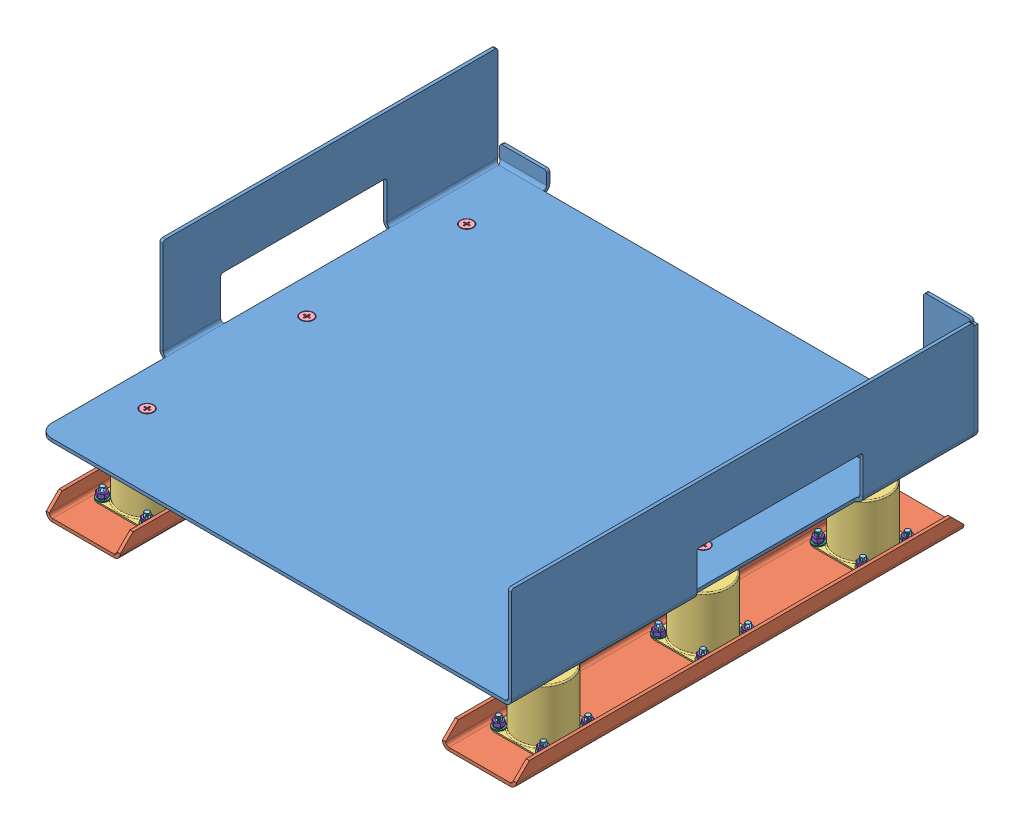
SolidWorks assembly В17.745.058СБ Шасси, configuration По умолчанию. Lengths in mm.
Overall size (375.45 141.9 365.44).
111 component instances, 8 part files, 203 mates.
Components (placement in the parent):
- В17.745.551 Полка-1: В17.745.551 Полка [По умолчанию<Как обработанный>] at (-182.6691 43.1061 558.1681) size (375.45 80.44 365.44)
- В17.745.556 Основание-1: В17.745.556 Основание [По умолчанию] at (-150.1691 -18.3939 375.6681) x (0 0 -1) z (1 0 0) size (350 15 58)
- В17.745.556 Основание-2: В17.745.556 Основание [По умолчанию] at (159.8309 -18.3939 375.6681) x (0 0 1) z (-1 0 0) size (350 15 58)
- В17.745.558 Амортизатор-1: В17.745.558 Амортизатор [По умолчанию] at (-150.1691 -17.3939 500.6681) size (44 59 44)
- В17.745.558 Амортизатор-2: В17.745.558 Амортизатор [По умолчанию] at (-150.1691 -17.3939 375.6681) size (44 59 44)
- В17.745.558 Амортизатор-3: В17.745.558 Амортизатор [По умолчанию] at (159.8309 -17.3939 375.6681) size (44 59 44)
- В17.745.558 Амортизатор-4: В17.745.558 Амортизатор [По умолчанию] at (159.8309 -17.3939 250.6681) size (44 59 44)
- В17.745.558 Амортизатор-5: В17.745.558 Амортизатор [По умолчанию] at (159.8309 -17.3939 500.6681) size (44 59 44)
- В17.745.558 Амортизатор-6: В17.745.558 Амортизатор [По умолчанию] at (-150.1691 -17.3939 250.6681) size (44 59 44)
- В17.745.557 Винт-1: В17.745.557 Винт [По умолчанию] at (159.8309 31.2061 250.6681) size (9.3 12.3 9.3)
- В17.745.557 Винт-2: В17.745.557 Винт [По умолчанию] at (159.8309 31.2061 500.6681) size (9.3 12.3 9.3)
- В17.745.557 Винт-3: В17.745.557 Винт [По умолчанию] at (159.8309 31.2061 375.6681) size (9.3 12.3 9.3)
- В17.745.557 Винт-4: В17.745.557 Винт [По умолчанию] at (-150.1691 31.2061 500.6681) size (9.3 12.3 9.3)
- В17.745.557 Винт-5: В17.745.557 Винт [По умолчанию] at (-150.1691 31.2061 375.6681) size (9.3 12.3 9.3)
- В17.745.557 Винт-6: В17.745.557 Винт [По умолчанию] at (-150.1691 31.2061 250.6681) size (9.3 12.3 9.3)
- В17.745.556 Винт-1: В17.745.556 Винт [По умолчанию] at (-132.6691 -9.2939 358.1681) x (1 0 0) z (0 0 -1) size (8.4 12.23 8.4)
- В17.745.556 Винт-2: В17.745.556 Винт [По умолчанию] at (-132.6691 -9.2939 393.1681) x (1 0 0) z (0 0 -1) size (8.4 12.23 8.4)
- В17.745.556 Винт-3: В17.745.556 Винт [По умолчанию] at (-132.6691 -9.2939 268.1681) x (1 0 0) z (0 0 -1) size (8.4 12.23 8.4)
- В17.745.556 Винт-4: В17.745.556 Винт [По умолчанию] at (-132.6691 -9.2939 233.1681) x (1 0 0) z (0 0 -1) size (8.4 12.23 8.4)
- В17.745.556 Винт-5: В17.745.556 Винт [По умолчанию] at (-167.6691 -9.2939 268.1681) x (1 0 0) z (0 0 -1) size (8.4 12.23 8.4)
- В17.745.556 Винт-6: В17.745.556 Винт [По умолчанию] at (-167.6691 -9.2939 233.1681) x (1 0 0) z (0 0 -1) size (8.4 12.23 8.4)
- В17.745.556 Винт-7: В17.745.556 Винт [По умолчанию] at (-167.6691 -9.2939 358.1681) x (1 0 0) z (0 0 -1) size (8.4 12.23 8.4)
- В17.745.556 Винт-8: В17.745.556 Винт [По умолчанию] at (-167.6691 -9.2939 393.1681) x (1 0 0) z (0 0 -1) size (8.4 12.23 8.4)
- В17.745.556 Винт-9: В17.745.556 Винт [По умолчанию] at (-132.6691 -9.2939 483.1681) x (1 0 0) z (0 0 -1) size (8.4 12.23 8.4)
- В17.745.556 Винт-10: В17.745.556 Винт [По умолчанию] at (-167.6691 -9.2939 483.1681) x (1 0 0) z (0 0 -1) size (8.4 12.23 8.4)
- В17.745.556 Винт-11: В17.745.556 Винт [По умолчанию] at (-132.6691 -9.2939 518.1681) x (1 0 0) z (0 0 -1) size (8.4 12.23 8.4)
- В17.745.556 Винт-12: В17.745.556 Винт [По умолчанию] at (-167.6691 -9.2939 518.1681) x (1 0 0) z (0 0 -1) size (8.4 12.23 8.4)
- В17.745.556 Винт-13: В17.745.556 Винт [По умолчанию] at (142.3309 -9.2939 393.1681) x (1 0 0) z (0 0 -1) size (8.4 12.23 8.4)
- В17.745.556 Винт-14: В17.745.556 Винт [По умолчанию] at (177.3309 -9.2939 393.1681) x (1 0 0) z (0 0 -1) size (8.4 12.23 8.4)
- В17.745.556 Винт-15: В17.745.556 Винт [По умолчанию] at (142.3309 -9.2939 358.1681) x (1 0 0) z (0 0 -1) size (8.4 12.23 8.4)
- В17.745.556 Винт-16: В17.745.556 Винт [По умолчанию] at (177.3309 -9.2939 358.1681) x (1 0 0) z (0 0 -1) size (8.4 12.23 8.4)
- В17.745.556 Винт-17: В17.745.556 Винт [По умолчанию] at (142.3309 -9.2939 268.1681) x (1 0 0) z (0 0 -1) size (8.4 12.23 8.4)
- В17.745.556 Винт-18: В17.745.556 Винт [По умолчанию] at (177.3309 -9.2939 233.1681) x (1 0 0) z (0 0 -1) size (8.4 12.23 8.4)
- В17.745.556 Винт-19: В17.745.556 Винт [По умолчанию] at (142.3309 -9.2939 233.1681) x (1 0 0) z (0 0 -1) size (8.4 12.23 8.4)
- В17.745.556 Винт-20: В17.745.556 Винт [По умолчанию] at (177.3309 -9.2939 268.1681) x (1 0 0) z (0 0 -1) size (8.4 12.23 8.4)
- В17.745.556 Винт-21: В17.745.556 Винт [По умолчанию] at (142.3309 -9.2939 483.1681) x (1 0 0) z (0 0 -1) size (8.4 12.23 8.4)
- В17.745.556 Винт-22: В17.745.556 Винт [По умолчанию] at (142.3309 -9.2939 518.1681) x (1 0 0) z (0 0 -1) size (8.4 12.23 8.4)
- В17.745.556 Винт-23: В17.745.556 Винт [По умолчанию] at (177.3309 -9.2939 518.1681) x (1 0 0) z (0 0 -1) size (8.4 12.23 8.4)
- В17.745.556 Винт-24: В17.745.556 Винт [По умолчанию] at (177.3309 -9.2939 483.1681) x (1 0 0) z (0 0 -1) size (8.4 12.23 8.4)
- В17.745.555 Шайба-1: В17.745.555 Шайба [По умолчанию] at (-167.6691 -17.3939 483.1681) size (9 0.8 9)
- В17.745.555 Шайба-2: В17.745.555 Шайба [По умолчанию] at (-167.6691 -17.3939 518.1681) size (9 0.8 9)
- В17.745.555 Шайба-3: В17.745.555 Шайба [По умолчанию] at (-132.6691 -17.3939 483.1681) size (9 0.8 9)
- В17.745.555 Шайба-4: В17.745.555 Шайба [По умолчанию] at (-132.6691 -17.3939 518.1681) size (9 0.8 9)
- В17.745.555 Шайба-5: В17.745.555 Шайба [По умолчанию] at (-132.6691 -17.3939 358.1681) size (9 0.8 9)
- В17.745.555 Шайба-6: В17.745.555 Шайба [По умолчанию] at (-167.6691 -17.3939 358.1681) x (0.667265 0 0.74482) z (-0.74482 0 0.667265) size (9 0.8 9)
- В17.745.555 Шайба-7: В17.745.555 Шайба [По умолчанию] at (-132.6691 -17.3939 393.1681) size (9 0.8 9)
- В17.745.555 Шайба-8: В17.745.555 Шайба [По умолчанию] at (-167.6691 -17.3939 393.1681) x (0.975059 0 0.221947) z (-0.221947 0 0.975059) size (9 0.8 9)
- В17.745.555 Шайба-9: В17.745.555 Шайба [По умолчанию] at (-167.6691 -17.3939 268.1681) size (9 0.8 9)
- В17.745.555 Шайба-10: В17.745.555 Шайба [По умолчанию] at (-132.6691 -17.3939 268.1681) size (9 0.8 9)
- В17.745.555 Шайба-11: В17.745.555 Шайба [По умолчанию] at (-167.6691 -17.3939 233.1681) size (9 0.8 9)
- В17.745.555 Шайба-12: В17.745.555 Шайба [По умолчанию] at (-132.6691 -17.3939 233.1681) size (9 0.8 9)
- В17.745.555 Шайба-13: В17.745.555 Шайба [По умолчанию] at (142.3309 -17.3939 518.1681) size (9 0.8 9)
- В17.745.555 Шайба-14: В17.745.555 Шайба [По умолчанию] at (142.3309 -17.3939 483.1681) size (9 0.8 9)
- В17.745.555 Шайба-15: В17.745.555 Шайба [По умолчанию] at (177.3309 -17.3939 483.1681) size (9 0.8 9)
- В17.745.555 Шайба-16: В17.745.555 Шайба [По умолчанию] at (177.3309 -17.3939 518.1681) size (9 0.8 9)
- В17.745.555 Шайба-17: В17.745.555 Шайба [По умолчанию] at (142.3309 -17.3939 358.1681) size (9 0.8 9)
- В17.745.555 Шайба-18: В17.745.555 Шайба [По умолчанию] at (177.3309 -17.3939 393.1681) size (9 0.8 9)
- В17.745.555 Шайба-19: В17.745.555 Шайба [По умолчанию] at (142.3309 -17.3939 393.1681) size (9 0.8 9)
- В17.745.555 Шайба-20: В17.745.555 Шайба [По умолчанию] at (177.3309 -17.3939 358.1681) size (9 0.8 9)
- В17.745.555 Шайба-21: В17.745.555 Шайба [По умолчанию] at (142.3309 -17.3939 268.1681) size (9 0.8 9)
- В17.745.555 Шайба-22: В17.745.555 Шайба [По умолчанию] at (142.3309 -17.3939 233.1681) size (9 0.8 9)
- В17.745.555 Шайба-23: В17.745.555 Шайба [По умолчанию] at (177.3309 -17.3939 233.1681) size (9 0.8 9)
- В17.745.555 Шайба-24: В17.745.555 Шайба [По умолчанию] at (177.3309 -17.3939 268.1681) size (9 0.8 9)
- В17.745.554 Шайба-1: В17.745.554 Шайба [По умолчанию] at (-132.6691 -16.5939 518.1681) x (-0.950092 0 -0.311971) z (0.311971 0 -0.950092) size (6.5 0.8 6.5)
- В17.745.554 Шайба-2: В17.745.554 Шайба [По умолчанию] at (-167.6691 -16.5939 518.1681) x (-0.964104 0 -0.265525) z (0.265525 0 -0.964104) size (6.5 0.8 6.5)
- В17.745.554 Шайба-3: В17.745.554 Шайба [По умолчанию] at (-167.6691 -16.5939 483.1681) x (-0.900004 0 -0.435881) z (0.435881 0 -0.900004) size (6.5 0.8 6.5)
- В17.745.554 Шайба-4: В17.745.554 Шайба [По умолчанию] at (-132.6691 -16.5939 483.1681) x (0.833959 0 0.551827) z (-0.551827 0 0.833959) size (6.5 0.8 6.5)
- В17.745.554 Шайба-5: В17.745.554 Шайба [По умолчанию] at (-167.6691 -16.5939 358.1681) x (0.466083 0 -0.884741) z (0.884741 0 0.466083) size (6.5 0.8 6.5)
- В17.745.554 Шайба-6: В17.745.554 Шайба [По умолчанию] at (-132.6691 -16.5939 358.1681) x (0.892908 0 0.450239) z (-0.450239 0 0.892908) size (6.5 0.8 6.5)
- В17.745.554 Шайба-7: В17.745.554 Шайба [По умолчанию] at (-167.6691 -16.5939 393.1681) x (-0.311106 0 -0.950375) z (0.950375 0 -0.311106) size (6.5 0.8 6.5)
- В17.745.554 Шайба-8: В17.745.554 Шайба [По умолчанию] at (-132.6691 -16.5939 393.1681) size (6.5 0.8 6.5)
- В17.745.554 Шайба-13: В17.745.554 Шайба [По умолчанию] at (-132.6691 -16.5939 233.1681) size (6.5 0.8 6.5)
- В17.745.554 Шайба-14: В17.745.554 Шайба [По умолчанию] at (-167.6691 -16.5939 268.1681) size (6.5 0.8 6.5)
- В17.745.554 Шайба-15: В17.745.554 Шайба [По умолчанию] at (-132.6691 -16.5939 268.1681) x (0.985052 0 -0.172259) z (0.172259 0 0.985052) size (6.5 0.8 6.5)
- В17.745.554 Шайба-16: В17.745.554 Шайба [По умолчанию] at (-167.6691 -16.5939 233.1681) size (6.5 0.8 6.5)
- В17.745.554 Шайба-17: В17.745.554 Шайба [По умолчанию] at (177.3309 -16.5939 518.1681) x (-0.952485 0 -0.304585) z (0.304585 0 -0.952485) size (6.5 0.8 6.5)
- В17.745.554 Шайба-19: В17.745.554 Шайба [По умолчанию] at (142.3309 -16.5939 518.1681) x (-0.742093 0 -0.670297) z (0.670297 0 -0.742093) size (6.5 0.8 6.5)
- В17.745.554 Шайба-20: В17.745.554 Шайба [По умолчанию] at (142.3309 -16.5939 483.1681) x (0.157887 0 -0.987457) z (0.987457 0 0.157887) size (6.5 0.8 6.5)
- В17.745.554 Шайба-21: В17.745.554 Шайба [По умолчанию] at (177.3309 -16.5939 483.1681) x (0.73951 0 0.673145) z (-0.673145 0 0.73951) size (6.5 0.8 6.5)
- В17.745.554 Шайба-22: В17.745.554 Шайба [По умолчанию] at (177.3309 -16.5939 233.1681) x (0.8131 0 0.582125) z (-0.582125 0 0.8131) size (6.5 0.8 6.5)
- В17.745.554 Шайба-23: В17.745.554 Шайба [По умолчанию] at (142.3309 -16.5939 233.1681) size (6.5 0.8 6.5)
- В17.745.554 Шайба-24: В17.745.554 Шайба [По умолчанию] at (142.3309 -16.5939 268.1681) size (6.5 0.8 6.5)
- В17.745.554 Шайба-25: В17.745.554 Шайба [По умолчанию] at (177.3309 -16.5939 268.1681) x (-0.997954 0 -0.063934) z (0.063934 0 -0.997954) size (6.5 0.8 6.5)
- В17.745.554 Шайба-26: В17.745.554 Шайба [По умолчанию] at (142.3309 -16.5939 358.1681) size (6.5 0.8 6.5)
- В17.745.554 Шайба-27: В17.745.554 Шайба [По умолчанию] at (142.3309 -16.5939 393.1681) size (6.5 0.8 6.5)
- В17.745.554 Шайба-28: В17.745.554 Шайба [По умолчанию] at (177.3309 -16.5939 358.1681) x (0.299403 0 0.954127) z (-0.954127 0 0.299403) size (6.5 0.8 6.5)
- В17.745.554 Шайба-29: В17.745.554 Шайба [По умолчанию] at (177.3309 -16.5939 393.1681) size (6.5 0.8 6.5)
- В17.745.553 Гайка-1: В17.745.553 Гайка [По умолчанию] at (142.3309 -15.7939 483.1681) size (6.78 3.14 7.83)
- В17.745.553 Гайка-2: В17.745.553 Гайка [По умолчанию] at (177.3309 -15.7939 483.1681) size (6.78 3.14 7.83)
- В17.745.553 Гайка-3: В17.745.553 Гайка [По умолчанию] at (177.3309 -15.7939 518.1681) size (6.78 3.14 7.83)
- В17.745.553 Гайка-4: В17.745.553 Гайка [По умолчанию] at (142.3309 -15.7939 518.1681) size (6.78 3.14 7.83)
- В17.745.553 Гайка-5: В17.745.553 Гайка [По умолчанию] at (142.3309 -16.5939 393.1681) size (6.78 3.14 7.83)
- В17.745.553 Гайка-6: В17.745.553 Гайка [По умолчанию] at (177.3309 -15.7939 393.1681) size (6.78 3.14 7.83)
- В17.745.553 Гайка-7: В17.745.553 Гайка [По умолчанию] at (177.3309 -15.7939 358.1681) size (6.78 3.14 7.83)
- В17.745.553 Гайка-8: В17.745.553 Гайка [По умолчанию] at (142.3309 -15.7939 358.1681) size (6.78 3.14 7.83)
- В17.745.553 Гайка-9: В17.745.553 Гайка [По умолчанию] at (177.3309 -15.7939 268.1681) size (6.78 3.14 7.83)
- В17.745.553 Гайка-10: В17.745.553 Гайка [По умолчанию] at (142.3309 -15.7939 233.1681) size (6.78 3.14 7.83)
- В17.745.553 Гайка-11: В17.745.553 Гайка [По умолчанию] at (177.3309 -15.7939 233.1681) size (6.78 3.14 7.83)
- В17.745.553 Гайка-12: В17.745.553 Гайка [По умолчанию] at (142.3309 -15.7939 268.1681) x (0.892685 0 0.450682) z (-0.450682 0 0.892685) size (6.78 3.14 7.83)
- В17.745.553 Гайка-13: В17.745.553 Гайка [По умолчанию] at (-167.6691 -15.7939 268.1681) size (6.78 3.14 7.83)
- В17.745.553 Гайка-14: В17.745.553 Гайка [По умолчанию] at (-167.6691 -15.7939 233.1681) size (6.78 3.14 7.83)
- В17.745.553 Гайка-15: В17.745.553 Гайка [По умолчанию] at (-132.6691 -15.7939 233.1681) x (0.109606 0 -0.993975) z (0.993975 0 0.109606) size (6.78 3.14 7.83)
- В17.745.553 Гайка-16: В17.745.553 Гайка [По умолчанию] at (-132.6691 -15.7939 268.1681) size (6.78 3.14 7.83)
- В17.745.553 Гайка-17: В17.745.553 Гайка [По умолчанию] at (-167.6691 -15.7939 358.1681) size (6.78 3.14 7.83)
- В17.745.553 Гайка-18: В17.745.553 Гайка [По умолчанию] at (-132.6691 -15.7939 393.1681) size (6.78 3.14 7.83)
- В17.745.553 Гайка-19: В17.745.553 Гайка [По умолчанию] at (-167.6691 -15.7939 393.1681) size (6.78 3.14 7.83)
- В17.745.553 Гайка-20: В17.745.553 Гайка [По умолчанию] at (-132.6691 -15.7939 358.1681) size (6.78 3.14 7.83)
- В17.745.553 Гайка-21: В17.745.553 Гайка [По умолчанию] at (-132.6691 -15.7939 483.1681) size (6.78 3.14 7.83)
- В17.745.553 Гайка-22: В17.745.553 Гайка [По умолчанию] at (-167.6691 -15.7939 518.1681) size (6.78 3.14 7.83)
- В17.745.553 Гайка-23: В17.745.553 Гайка [По умолчанию] at (-132.6691 -15.7939 518.1681) size (6.78 3.14 7.83)
- В17.745.553 Гайка-24: В17.745.553 Гайка [По умолчанию] at (-167.6691 -15.7939 483.1681) size (6.78 3.14 7.83)
Mates (geometry in assembly coordinates):
- Концентричный1: concentric aligned: circle of 1_Полка-1; circle of 8_Амортизатор-6
- Совпадение2: coincident anti-aligned: plane of 1_Полка-1 through (-182.6691 40.6061 558.1681) normal (0 -1 0); plane of 8_Амортизатор-6 through (-150.1691 40.6061 250.6681) normal (0 1 0)
- Совпадение3: coincident aligned: cone of 1_Полка-1 through (-150.1691 40.7561 250.6681) axis (0 -1 0); cone of 7_Винт_М5-6 through (-150.1691 42.6561 250.6681) axis (0 -1 0)
- Концентричный2: concentric aligned: circle of 1_Полка-1; circle of 8_Амортизатор-2
- Совпадение4: coincident anti-aligned: plane of 1_Полка-1 through (-182.6691 40.6061 558.1681) normal (0 -1 0); plane of 8_Амортизатор-2 through (-150.1691 40.6061 375.6681) normal (0 1 0)
- Концентричный3: concentric aligned: circle of 1_Полка-1; circle of 8_Амортизатор-1
- Совпадение5: coincident anti-aligned: plane of 1_Полка-1 through (-182.6691 40.6061 558.1681) normal (0 -1 0); plane of 8_Амортизатор-1 through (-150.1691 40.6061 500.6681) normal (0 1 0)
- Концентричный4: concentric aligned: circle of 1_Полка-1; circle of 8_Амортизатор-4
- Совпадение6: coincident anti-aligned: plane of 1_Полка-1 through (-182.6691 40.6061 558.1681) normal (0 -1 0); plane of 8_Амортизатор-4 through (159.8309 40.6061 250.6681) normal (0 1 0)
- Концентричный5: concentric aligned: circle of 1_Полка-1; circle of 8_Амортизатор-3
- Совпадение7: coincident anti-aligned: plane of 1_Полка-1 through (-182.6691 40.6061 558.1681) normal (0 -1 0); plane of 8_Амортизатор-3 through (159.8309 40.6061 375.6681) normal (0 1 0)
- Концентричный6: concentric aligned: circle of 1_Полка-1; circle of 8_Амортизатор-5
- Совпадение8: coincident anti-aligned: plane of 1_Полка-1 through (-182.6691 40.6061 558.1681) normal (0 -1 0); plane of 8_Амортизатор-5 through (159.8309 40.6061 500.6681) normal (0 1 0)
- Совпадение9: coincident aligned: cone of 1_Полка-1 through (-150.1691 40.7561 375.6681) axis (0 -1 0); cone of 7_Винт_М5-5 through (-150.1691 42.6561 375.6681) axis (0 -1 0)
- Совпадение10: coincident aligned: cone of 1_Полка-1 through (-150.1691 40.7561 500.6681) axis (0 -1 0); cone of 7_Винт_М5-4 through (-150.1691 42.6561 500.6681) axis (0 -1 0)
- Совпадение11: coincident aligned: cone of 1_Полка-1 through (159.8309 40.7561 500.6681) axis (0 -1 0); cone of 7_Винт_М5-2 through (159.8309 42.6561 500.6681) axis (0 -1 0)
- Совпадение12: coincident aligned: cone of 1_Полка-1 through (159.8309 40.7561 375.6681) axis (0 -1 0); cone of 7_Винт_М5-3 through (159.8309 42.6561 375.6681) axis (0 -1 0)
- Совпадение14: coincident aligned: cone of 1_Полка-1 through (159.8309 40.7561 250.6681) axis (0 -1 0); cone of 7_Винт_М5-1 through (159.8309 42.6561 250.6681) axis (0 -1 0)
- Концентричный11: concentric aligned: circle of 2_Основание-1; circle of 8_Амортизатор-6
- Концентричный12: concentric aligned: circle of 2_Основание-1; circle of 8_Амортизатор-6
- Концентричный13: concentric aligned: circle of 2_Основание-1; circle of 8_Амортизатор-2
- Концентричный14: concentric anti-aligned: cylinder of 2_Основание-1; cylinder of 8_Амортизатор-2 through (-132.6691 24.8061 393.1681) axis (0 -1 0) radius 2
- Концентричный15: concentric anti-aligned: circle of 2_Основание-1; cylinder of 8_Амортизатор-1 through (-167.6691 24.8061 483.1681) axis (0 -1 0) radius 2
- Концентричный16: concentric aligned: circle of 2_Основание-1; circle of 8_Амортизатор-1
- Совпадение15: coincident anti-aligned: plane of 2_Основание-1 through (-150.1691 -18.3939 375.6681) normal (0 1 0); plane of 8_Амортизатор-1 through (-150.1691 -18.3939 500.6681) normal (0 -1 0)
- Совпадение16: coincident aligned: cone of 2_Основание-1 through (-167.6691 -20.8939 518.1681) axis (0 1 0); cone of 6_Винт_М4-12 through (-167.6691 -20.7939 518.1681) axis (0 1 0)
- Совпадение17: coincident aligned: cone of 2_Основание-1 through (-132.6691 -20.8939 518.1681) axis (0 1 0); cone of 6_Винт_М4-11 through (-132.6691 -20.7939 518.1681) axis (0 1 0)
- Совпадение18: coincident anti-aligned: cone of 2_Основание-1 through (-167.6691 -20.8939 483.1681) axis (0 1 0); circle of 6_Винт_М4-10
- Совпадение19: coincident anti-aligned: cone of 2_Основание-1 through (-132.6691 -20.8939 483.1681) axis (0 1 0); circle of 6_Винт_М4-9
- Совпадение20: coincident aligned: cone of 2_Основание-1 through (-167.6691 -20.8939 393.1681) axis (0 1 0); cone of 6_Винт_М4-8 through (-167.6691 -20.7939 393.1681) axis (0 1 0)
- Совпадение21: coincident aligned: cone of 2_Основание-1 through (-132.6691 -20.8939 358.1681) axis (0 1 0); cone of 6_Винт_М4-1 through (-132.6691 -20.7939 358.1681) axis (0 1 0)
- Совпадение22: coincident aligned: cone of 2_Основание-1 through (-167.6691 -20.8939 358.1681) axis (0 1 0); cone of 6_Винт_М4-7 through (-167.6691 -20.7939 358.1681) axis (0 1 0)
- Совпадение23: coincident aligned: cone of 2_Основание-1 through (-132.6691 -20.8939 393.1681) axis (0 1 0); cone of 6_Винт_М4-2 through (-132.6691 -20.7939 393.1681) axis (0 1 0)
- Совпадение24: coincident aligned: cone of 2_Основание-1 through (-167.6691 -20.8939 268.1681) axis (0 1 0); cone of 6_Винт_М4-5 through (-167.6691 -20.7939 268.1681) axis (0 1 0)
- Совпадение25: coincident aligned: cone of 2_Основание-1 through (-167.6691 -20.8939 233.1681) axis (0 1 0); cone of 6_Винт_М4-6 through (-167.6691 -20.7939 233.1681) axis (0 1 0)
- Совпадение26: coincident aligned: cone of 2_Основание-1 through (-132.6691 -20.8939 233.1681) axis (0 1 0); cone of 6_Винт_М4-4 through (-132.6691 -20.7939 233.1681) axis (0 1 0)
- Совпадение27: coincident aligned: cone of 2_Основание-1 through (-132.6691 -20.8939 268.1681) axis (0 1 0); cone of 6_Винт_М4-3 through (-132.6691 -20.7939 268.1681) axis (0 1 0)
- Концентричный17: concentric anti-aligned: circle of 2_Основание-2; cylinder of 8_Амортизатор-5 through (142.3309 24.8061 483.1681) axis (0 -1 0) radius 2
- Концентричный18: concentric anti-aligned: circle of 2_Основание-2; cylinder of 8_Амортизатор-5 through (177.3309 24.8061 518.1681) axis (0 -1 0) radius 2
- Концентричный19: concentric anti-aligned: circle of 2_Основание-2; cylinder of 8_Амортизатор-3 through (142.3309 24.8061 393.1681) axis (0 -1 0) radius 2
- Концентричный20: concentric aligned: circle of 2_Основание-2; circle of 8_Амортизатор-3
- Концентричный21: concentric anti-aligned: circle of 2_Основание-2; cylinder of 8_Амортизатор-4 through (142.3309 24.8061 268.1681) axis (0 -1 0) radius 2
- Концентричный22: concentric anti-aligned: circle of 2_Основание-2; cylinder of 8_Амортизатор-4 through (177.3309 24.8061 233.1681) axis (0 -1 0) radius 2
- Совпадение28: coincident anti-aligned: plane of 2_Основание-2 through (159.8309 -18.3939 375.6681) normal (0 1 0); plane of 8_Амортизатор-5 through (159.8309 -18.3939 500.6681) normal (0 -1 0)
- Совпадение29: coincident aligned: cone of 2_Основание-2 through (142.3309 -20.8939 518.1681) axis (0 1 0); cone of 6_Винт_М4-22 through (142.3309 -20.7939 518.1681) axis (0 1 0)
- Совпадение30: coincident aligned: cone of 2_Основание-2 through (177.3309 -20.8939 518.1681) axis (0 1 0); cone of 6_Винт_М4-23 through (177.3309 -20.7939 518.1681) axis (0 1 0)
- Совпадение31: coincident aligned: cone of 2_Основание-2 through (142.3309 -20.8939 483.1681) axis (0 1 0); cone of 6_Винт_М4-21 through (142.3309 -20.7939 483.1681) axis (0 1 0)
- Совпадение32: coincident aligned: cone of 2_Основание-2 through (177.3309 -20.8939 483.1681) axis (0 1 0); cone of 6_Винт_М4-24 through (177.3309 -20.7939 483.1681) axis (0 1 0)
- Совпадение33: coincident aligned: cone of 2_Основание-2 through (142.3309 -20.8939 393.1681) axis (0 1 0); cone of 6_Винт_М4-13 through (142.3309 -20.7939 393.1681) axis (0 1 0)
- Совпадение34: coincident aligned: cone of 2_Основание-2 through (177.3309 -20.8939 393.1681) axis (0 1 0); cone of 6_Винт_М4-14 through (177.3309 -20.7939 393.1681) axis (0 1 0)
- Совпадение35: coincident aligned: cone of 2_Основание-2 through (142.3309 -20.8939 358.1681) axis (0 1 0); cone of 6_Винт_М4-15 through (142.3309 -20.7939 358.1681) axis (0 1 0)
- Совпадение36: coincident aligned: cone of 2_Основание-2 through (177.3309 -20.8939 358.1681) axis (0 1 0); cone of 6_Винт_М4-16 through (177.3309 -20.7939 358.1681) axis (0 1 0)
- Совпадение37: coincident aligned: cone of 2_Основание-2 through (142.3309 -20.8939 268.1681) axis (0 1 0); cone of 6_Винт_М4-17 through (142.3309 -20.7939 268.1681) axis (0 1 0)
- Совпадение38: coincident aligned: cone of 2_Основание-2 through (177.3309 -20.8939 233.1681) axis (0 1 0); cone of 6_Винт_М4-18 through (177.3309 -20.7939 233.1681) axis (0 1 0)
- Совпадение39: coincident aligned: cone of 2_Основание-2 through (177.3309 -20.8939 268.1681) axis (0 1 0); cone of 6_Винт_М4-20 through (177.3309 -20.7939 268.1681) axis (0 1 0)
- Совпадение40: coincident aligned: cone of 2_Основание-2 through (142.3309 -20.8939 233.1681) axis (0 1 0); cone of 6_Винт_М4-19 through (142.3309 -20.7939 233.1681) axis (0 1 0)
- Совпадение43: coincident anti-aligned: plane of 8_Амортизатор-1 through (-150.1691 -17.3939 500.6681) normal (0 1 0); plane of 5_Шайба_А4-2 through (-167.6691 -17.3939 518.1681) normal (0 -1 0)
- Концентричный24: concentric aligned: circle of 8_Амортизатор-1; circle of 5_Шайба_А4-2
- Совпадение44: coincident anti-aligned: plane of 8_Амортизатор-1 through (-150.1691 -17.3939 500.6681) normal (0 1 0); plane of 5_Шайба_А4-4 through (-132.6691 -17.3939 518.1681) normal (0 -1 0)
- Концентричный25: concentric aligned: circle of 8_Амортизатор-1; circle of 5_Шайба_А4-4
- Совпадение45: coincident anti-aligned: plane of 8_Амортизатор-1 through (-150.1691 -17.3939 500.6681) normal (0 1 0); plane of 5_Шайба_А4-1 through (-167.6691 -17.3939 483.1681) normal (0 -1 0)
- Концентричный26: concentric aligned: circle of 8_Амортизатор-1; circle of 5_Шайба_А4-1
- Совпадение46: coincident aligned: plane of 8_Амортизатор-1 through (-150.1691 -17.3939 500.6681) normal (0 1 0); circle of 5_Шайба_А4-3
- Концентричный27: concentric aligned: circle of 8_Амортизатор-1; circle of 5_Шайба_А4-3
- Концентричный28: concentric aligned: circle of 8_Амортизатор-2; circle of 5_Шайба_А4-7
- Совпадение47: coincident anti-aligned: plane of 8_Амортизатор-2 through (-150.1691 -17.3939 375.6681) normal (0 1 0); plane of 5_Шайба_А4-7 through (-132.6691 -17.3939 393.1681) normal (0 -1 0)
- Концентричный29: concentric aligned: circle of 8_Амортизатор-2; circle of 5_Шайба_А4-8
- Совпадение49: coincident anti-aligned: plane of 8_Амортизатор-2 through (-150.1691 -17.3939 375.6681) normal (0 1 0); plane of 5_Шайба_А4-8 through (-167.6691 -17.3939 393.1681) normal (0 -1 0)
- Концентричный30: concentric aligned: circle of 8_Амортизатор-2; circle of 5_Шайба_А4-6
- Совпадение51: coincident anti-aligned: plane of 8_Амортизатор-2 through (-150.1691 -17.3939 375.6681) normal (0 1 0); plane of 5_Шайба_А4-6 through (-167.6691 -17.3939 358.1681) normal (0 -1 0)
- Концентричный31: concentric aligned: circle of 8_Амортизатор-2; circle of 5_Шайба_А4-5
- Совпадение54: coincident anti-aligned: plane of 8_Амортизатор-2 through (-150.1691 -17.3939 375.6681) normal (0 1 0); plane of 5_Шайба_А4-5 through (-132.6691 -17.3939 358.1681) normal (0 -1 0)
- Концентричный32: concentric aligned: circle of 8_Амортизатор-6; circle of 5_Шайба_А4-9
- Совпадение55: coincident anti-aligned: plane of 8_Амортизатор-6 through (-150.1691 -17.3939 250.6681) normal (0 1 0); plane of 5_Шайба_А4-9 through (-167.6691 -17.3939 268.1681) normal (0 -1 0)
- Совпадение56: coincident anti-aligned: plane of 8_Амортизатор-6 through (-150.1691 -17.3939 250.6681) normal (0 1 0); plane of 5_Шайба_А4-11 through (-167.6691 -17.3939 233.1681) normal (0 -1 0)
- Совпадение57: coincident anti-aligned: plane of 8_Амортизатор-6 through (-150.1691 -17.3939 250.6681) normal (0 1 0); plane of 5_Шайба_А4-10 through (-132.6691 -17.3939 268.1681) normal (0 -1 0)
- Совпадение58: coincident aligned: plane of 8_Амортизатор-6 through (-150.1691 -17.3939 250.6681) normal (0 1 0); circle of 5_Шайба_А4-12
- Концентричный33: concentric aligned: circle of 8_Амортизатор-6; circle of 5_Шайба_А4-12
- Концентричный34: concentric aligned: circle of 8_Амортизатор-6; circle of 5_Шайба_А4-11
- Концентричный35: concentric aligned: circle of 8_Амортизатор-6; circle of 5_Шайба_А4-10
- Совпадение59: coincident aligned: plane of 5_Шайба_А4-23 through (177.3309 -17.3939 233.1681) normal (0 -1 0); plane of 5_Шайба_А4-24 through (177.3309 -17.3939 268.1681) normal (0 -1 0)
- Совпадение60: coincident aligned: plane of 5_Шайба_А4-21 through (142.3309 -17.3939 268.1681) normal (0 -1 0); plane of 5_Шайба_А4-23 through (177.3309 -17.3939 233.1681) normal (0 -1 0)
- Совпадение61: coincident aligned: plane of 5_Шайба_А4-22 through (142.3309 -17.3939 233.1681) normal (0 -1 0); plane of 5_Шайба_А4-23 through (177.3309 -17.3939 233.1681) normal (0 -1 0)
- Совпадение62: coincident anti-aligned: plane of 8_Амортизатор-4 through (159.8309 -17.3939 250.6681) normal (0 1 0); plane of 5_Шайба_А4-23 through (177.3309 -17.3939 233.1681) normal (0 -1 0)
- Совпадение63: coincident anti-aligned: plane of 8_Амортизатор-4 through (159.8309 -17.3939 250.6681) normal (0 1 0); plane of 5_Шайба_А4-22 through (142.3309 -17.3939 233.1681) normal (0 -1 0)
- Совпадение64: coincident anti-aligned: plane of 8_Амортизатор-4 through (159.8309 -17.3939 250.6681) normal (0 1 0); plane of 5_Шайба_А4-21 through (142.3309 -17.3939 268.1681) normal (0 -1 0)
- Совпадение65: coincident anti-aligned: plane of 8_Амортизатор-4 through (159.8309 -17.3939 250.6681) normal (0 1 0); plane of 5_Шайба_А4-24 through (177.3309 -17.3939 268.1681) normal (0 -1 0)
- Концентричный36: concentric aligned: circle of 8_Амортизатор-4; circle of 5_Шайба_А4-24
- Концентричный37: concentric aligned: circle of 8_Амортизатор-4; circle of 5_Шайба_А4-21
- Концентричный38: concentric aligned: circle of 8_Амортизатор-4; circle of 5_Шайба_А4-23
- Концентричный39: concentric aligned: circle of 8_Амортизатор-4; circle of 5_Шайба_А4-22
- Совпадение66: coincident anti-aligned: plane of 8_Амортизатор-3 through (159.8309 -17.3939 375.6681) normal (0 1 0); plane of 5_Шайба_А4-18 through (177.3309 -17.3939 393.1681) normal (0 -1 0)
- Концентричный40: concentric aligned: circle of 8_Амортизатор-3; circle of 5_Шайба_А4-18
- Совпадение67: coincident anti-aligned: plane of 8_Амортизатор-3 through (159.8309 -17.3939 375.6681) normal (0 1 0); plane of 5_Шайба_А4-20 through (177.3309 -17.3939 358.1681) normal (0 -1 0)
- Концентричный41: concentric aligned: circle of 8_Амортизатор-3; circle of 5_Шайба_А4-20
- Совпадение68: coincident anti-aligned: plane of 8_Амортизатор-3 through (159.8309 -17.3939 375.6681) normal (0 1 0); plane of 5_Шайба_А4-17 through (142.3309 -17.3939 358.1681) normal (0 -1 0)
- Концентричный42: concentric aligned: circle of 8_Амортизатор-3; circle of 5_Шайба_А4-17
- Совпадение69: coincident anti-aligned: plane of 8_Амортизатор-3 through (159.8309 -17.3939 375.6681) normal (0 1 0); plane of 5_Шайба_А4-19 through (142.3309 -17.3939 393.1681) normal (0 -1 0)
- Концентричный43: concentric aligned: circle of 8_Амортизатор-3; circle of 5_Шайба_А4-19
- Совпадение70: coincident anti-aligned: plane of 8_Амортизатор-5 through (159.8309 -17.3939 500.6681) normal (0 1 0); plane of 5_Шайба_А4-15 through (177.3309 -17.3939 483.1681) normal (0 -1 0)
- Концентричный44: concentric aligned: circle of 8_Амортизатор-5; circle of 5_Шайба_А4-15
- Совпадение71: coincident anti-aligned: plane of 8_Амортизатор-5 through (159.8309 -17.3939 500.6681) normal (0 1 0); plane of 5_Шайба_А4-14 through (142.3309 -17.3939 483.1681) normal (0 -1 0)
- Концентричный45: concentric anti-aligned: circle of 8_Амортизатор-5; cylinder of 5_Шайба_А4-14 through (142.3309 -16.5939 483.1681) axis (0 -1 0) radius 2.15
- Совпадение72: coincident anti-aligned: plane of 8_Амортизатор-5 through (159.8309 -17.3939 500.6681) normal (0 1 0); plane of 5_Шайба_А4-13 through (142.3309 -17.3939 518.1681) normal (0 -1 0)
- Концентричный46: concentric aligned: circle of 8_Амортизатор-5; circle of 5_Шайба_А4-13
- Совпадение73: coincident anti-aligned: plane of 8_Амортизатор-5 through (159.8309 -17.3939 500.6681) normal (0 1 0); plane of 5_Шайба_А4-16 through (177.3309 -17.3939 518.1681) normal (0 -1 0)
- Концентричный47: concentric aligned: circle of 8_Амортизатор-5; circle of 5_Шайба_А4-16
- Совпадение74: coincident anti-aligned: plane of 5_Шайба_А4-1 through (-167.6691 -16.5939 483.1681) normal (0 1 0); plane of 4_Шайба-3 through (-167.6691 -16.5939 483.1681) normal (0 -1 0)
- Концентричный48: concentric aligned: circle of 5_Шайба_А4-1; circle of 4_Шайба-3
- Совпадение75: coincident anti-aligned: plane of 5_Шайба_А4-2 through (-167.6691 -16.5939 518.1681) normal (0 1 0); plane of 4_Шайба-2 through (-167.6691 -16.5939 518.1681) normal (0 -1 0)
- Концентричный49: concentric aligned: circle of 5_Шайба_А4-2; circle of 4_Шайба-2
- Совпадение76: coincident anti-aligned: plane of 5_Шайба_А4-4 through (-132.6691 -16.5939 518.1681) normal (0 1 0); plane of 4_Шайба-1 through (-132.6691 -16.5939 518.1681) normal (0 -1 0)
- Концентричный50: concentric aligned: circle of 5_Шайба_А4-4; circle of 4_Шайба-1
- Совпадение77: coincident anti-aligned: plane of 5_Шайба_А4-3 through (-132.6691 -16.5939 483.1681) normal (0 1 0); plane of 4_Шайба-4 through (-132.6691 -16.5939 483.1681) normal (0 -1 0)
- Концентричный51: concentric aligned: circle of 5_Шайба_А4-3; circle of 4_Шайба-4
- Совпадение78: coincident anti-aligned: plane of 5_Шайба_А4-8 through (-167.6691 -16.5939 393.1681) normal (0 1 0); plane of 4_Шайба-7 through (-167.6691 -16.5939 393.1681) normal (0 -1 0)
- Концентричный52: concentric aligned: circle of 5_Шайба_А4-8; circle of 4_Шайба-7
- Совпадение79: coincident anti-aligned: plane of 5_Шайба_А4-6 through (-167.6691 -16.5939 358.1681) normal (0 1 0); plane of 4_Шайба-5 through (-167.6691 -16.5939 358.1681) normal (0 -1 0)
- Концентричный53: concentric aligned: circle of 5_Шайба_А4-6; circle of 4_Шайба-5
- Совпадение80: coincident aligned: plane of 5_Шайба_А4-7 through (-132.6691 -16.5939 393.1681) normal (0 1 0); circle of 4_Шайба-8
- Концентричный56: concentric aligned: circle of 5_Шайба_А4-7; circle of 4_Шайба-8
- Совпадение82: coincident anti-aligned: plane of 5_Шайба_А4-5 through (-132.6691 -16.5939 358.1681) normal (0 1 0); plane of 4_Шайба-6 through (-132.6691 -16.5939 358.1681) normal (0 -1 0)
- Концентричный57: concentric aligned: circle of 5_Шайба_А4-5; circle of 4_Шайба-6
- Совпадение83: coincident anti-aligned: plane of 5_Шайба_А4-12 through (-132.6691 -16.5939 233.1681) normal (0 1 0); plane of 4_Шайба-13 through (-132.6691 -16.5939 233.1681) normal (0 -1 0)
- Концентричный58: concentric aligned: circle of 5_Шайба_А4-12; circle of 4_Шайба-13
- Совпадение84: coincident anti-aligned: plane of 5_Шайба_А4-11 through (-167.6691 -16.5939 233.1681) normal (0 1 0); plane of 4_Шайба-16 through (-167.6691 -16.5939 233.1681) normal (0 -1 0)
- Концентричный59: concentric aligned: circle of 5_Шайба_А4-11; circle of 4_Шайба-16
- Совпадение85: coincident anti-aligned: plane of 5_Шайба_А4-9 through (-167.6691 -16.5939 268.1681) normal (0 1 0); plane of 4_Шайба-14 through (-167.6691 -16.5939 268.1681) normal (0 -1 0)
- Концентричный60: concentric aligned: circle of 5_Шайба_А4-9; circle of 4_Шайба-14
- Концентричный61: concentric aligned: circle of 5_Шайба_А4-10; circle of 4_Шайба-15
- Совпадение88: coincident aligned: plane of 5_Шайба_А4-10 through (-132.6691 -16.5939 268.1681) normal (0 1 0); circle of 4_Шайба-15
- Совпадение89: coincident anti-aligned: plane of 5_Шайба_А4-13 through (142.3309 -16.5939 518.1681) normal (0 1 0); plane of 4_Шайба-19 through (142.3309 -16.5939 518.1681) normal (0 -1 0)
- Концентричный63: concentric aligned: circle of 5_Шайба_А4-13; circle of 4_Шайба-19
- Совпадение90: coincident anti-aligned: plane of 5_Шайба_А4-16 through (177.3309 -16.5939 518.1681) normal (0 1 0); plane of 4_Шайба-17 through (177.3309 -16.5939 518.1681) normal (0 -1 0)
- Концентричный64: concentric aligned: circle of 5_Шайба_А4-16; circle of 4_Шайба-17
- Совпадение91: coincident anti-aligned: plane of 5_Шайба_А4-14 through (142.3309 -16.5939 483.1681) normal (0 1 0); plane of 4_Шайба-20 through (142.3309 -16.5939 483.1681) normal (0 -1 0)
- Концентричный65: concentric aligned: circle of 5_Шайба_А4-14; circle of 4_Шайба-20
- Совпадение92: coincident anti-aligned: plane of 5_Шайба_А4-15 through (177.3309 -16.5939 483.1681) normal (0 1 0); plane of 4_Шайба-21 through (177.3309 -16.5939 483.1681) normal (0 -1 0)
- Концентричный66: concentric aligned: circle of 5_Шайба_А4-15; circle of 4_Шайба-21
- Совпадение93: coincident anti-aligned: plane of 5_Шайба_А4-21 through (142.3309 -16.5939 268.1681) normal (0 1 0); plane of 4_Шайба-24 through (142.3309 -16.5939 268.1681) normal (0 -1 0)
- Концентричный67: concentric aligned: circle of 5_Шайба_А4-21; circle of 4_Шайба-24
- Совпадение94: coincident anti-aligned: plane of 5_Шайба_А4-24 through (177.3309 -16.5939 268.1681) normal (0 1 0); plane of 4_Шайба-25 through (177.3309 -16.5939 268.1681) normal (0 -1 0)
- Концентричный68: concentric aligned: circle of 5_Шайба_А4-24; circle of 4_Шайба-25
- Совпадение95: coincident anti-aligned: plane of 5_Шайба_А4-23 through (177.3309 -16.5939 233.1681) normal (0 1 0); plane of 4_Шайба-22 through (177.3309 -16.5939 233.1681) normal (0 -1 0)
- Концентричный69: concentric aligned: circle of 5_Шайба_А4-23; circle of 4_Шайба-22
- Совпадение96: coincident anti-aligned: plane of 5_Шайба_А4-22 through (142.3309 -16.5939 233.1681) normal (0 1 0); plane of 4_Шайба-23 through (142.3309 -16.5939 233.1681) normal (0 -1 0)
- Концентричный70: concentric aligned: circle of 5_Шайба_А4-22; circle of 4_Шайба-23
- Совпадение97: coincident anti-aligned: plane of 5_Шайба_А4-17 through (142.3309 -16.5939 358.1681) normal (0 1 0); plane of 4_Шайба-26 through (142.3309 -16.5939 358.1681) normal (0 -1 0)
- Концентричный71: concentric aligned: circle of 5_Шайба_А4-17; circle of 4_Шайба-26
- Совпадение98: coincident anti-aligned: plane of 5_Шайба_А4-19 through (142.3309 -16.5939 393.1681) normal (0 1 0); plane of 4_Шайба-27 through (142.3309 -16.5939 393.1681) normal (0 -1 0)
- Концентричный72: concentric aligned: circle of 5_Шайба_А4-19; circle of 4_Шайба-27
- Совпадение99: coincident anti-aligned: plane of 5_Шайба_А4-18 through (177.3309 -16.5939 393.1681) normal (0 1 0); plane of 4_Шайба-29 through (177.3309 -16.5939 393.1681) normal (0 -1 0)
- Концентричный73: concentric aligned: circle of 5_Шайба_А4-18; circle of 4_Шайба-29
- Совпадение100: coincident anti-aligned: plane of 5_Шайба_А4-20 through (177.3309 -16.5939 358.1681) normal (0 1 0); plane of 4_Шайба-28 through (177.3309 -16.5939 358.1681) normal (0 -1 0)
- Концентричный74: concentric aligned: circle of 5_Шайба_А4-20; circle of 4_Шайба-28
- Совпадение101: coincident anti-aligned: plane of 4_Шайба-19 through (142.3309 -15.7939 518.1681) normal (0 1 0); plane of 3_Гайка-4 through (142.3309 -15.7939 518.1681) normal (0 -1 0)
- Концентричный75: concentric aligned: circle of 4_Шайба-19; circle of 3_Гайка-4
- Совпадение102: coincident anti-aligned: plane of 4_Шайба-20 through (142.3309 -15.7939 483.1681) normal (0 1 0); plane of 3_Гайка-1 through (142.3309 -15.7939 483.1681) normal (0 -1 0)
- Концентричный76: concentric aligned: circle of 4_Шайба-20; circle of 3_Гайка-1
- Совпадение103: coincident anti-aligned: plane of 4_Шайба-21 through (177.3309 -15.7939 483.1681) normal (0 1 0); plane of 3_Гайка-2 through (177.3309 -15.7939 483.1681) normal (0 -1 0)
- Концентричный77: concentric aligned: circle of 4_Шайба-21; circle of 3_Гайка-2
- Совпадение104: coincident anti-aligned: plane of 4_Шайба-17 through (177.3309 -15.7939 518.1681) normal (0 1 0); plane of 3_Гайка-3 through (177.3309 -15.7939 518.1681) normal (0 -1 0)
- Концентричный78: concentric aligned: circle of 4_Шайба-17; circle of 3_Гайка-3
- Совпадение106: coincident anti-aligned: plane of 5_Шайба_А4-19 through (142.3309 -16.5939 393.1681) normal (0 1 0); plane of 3_Гайка-5 through (142.3309 -16.5939 393.1681) normal (0 -1 0)
- Концентричный79: concentric aligned: circle of 4_Шайба-27; circle of 3_Гайка-5
- Совпадение107: coincident anti-aligned: plane of 4_Шайба-29 through (177.3309 -15.7939 393.1681) normal (0 1 0); plane of 3_Гайка-6 through (177.3309 -15.7939 393.1681) normal (0 -1 0)
- Концентричный80: concentric aligned: circle of 4_Шайба-29; circle of 3_Гайка-6
- Совпадение108: coincident anti-aligned: plane of 4_Шайба-28 through (177.3309 -15.7939 358.1681) normal (0 1 0); plane of 3_Гайка-7 through (177.3309 -15.7939 358.1681) normal (0 -1 0)
- Концентричный81: concentric aligned: circle of 4_Шайба-28; circle of 3_Гайка-7
- Совпадение109: coincident anti-aligned: plane of 4_Шайба-26 through (142.3309 -15.7939 358.1681) normal (0 1 0); plane of 3_Гайка-8 through (142.3309 -15.7939 358.1681) normal (0 -1 0)
- Концентричный82: concentric aligned: circle of 4_Шайба-26; circle of 3_Гайка-8
- Совпадение110: coincident anti-aligned: plane of 4_Шайба-22 through (177.3309 -15.7939 233.1681) normal (0 1 0); plane of 3_Гайка-11 through (177.3309 -15.7939 233.1681) normal (0 -1 0)
- Концентричный83: concentric aligned: circle of 4_Шайба-22; circle of 3_Гайка-11
- Совпадение111: coincident anti-aligned: plane of 4_Шайба-25 through (177.3309 -15.7939 268.1681) normal (0 1 0); plane of 3_Гайка-9 through (177.3309 -15.7939 268.1681) normal (0 -1 0)
- Концентричный84: concentric aligned: circle of 4_Шайба-25; circle of 3_Гайка-9
- Совпадение112: coincident anti-aligned: plane of 4_Шайба-24 through (142.3309 -15.7939 268.1681) normal (0 1 0); plane of 3_Гайка-12 through (142.3309 -15.7939 268.1681) normal (0 -1 0)
- Концентричный85: concentric aligned: circle of 4_Шайба-24; circle of 3_Гайка-12
- Совпадение113: coincident anti-aligned: plane of 4_Шайба-23 through (142.3309 -15.7939 233.1681) normal (0 1 0); plane of 3_Гайка-10 through (142.3309 -15.7939 233.1681) normal (0 -1 0)
- Концентричный86: concentric aligned: circle of 4_Шайба-23; circle of 3_Гайка-10
- Совпадение114: coincident anti-aligned: plane of 4_Шайба-14 through (-167.6691 -15.7939 268.1681) normal (0 1 0); plane of 3_Гайка-13 through (-167.6691 -15.7939 268.1681) normal (0 -1 0)
- Концентричный87: concentric aligned: circle of 4_Шайба-14; circle of 3_Гайка-13
- Совпадение115: coincident anti-aligned: plane of 4_Шайба-16 through (-167.6691 -15.7939 233.1681) normal (0 1 0); plane of 3_Гайка-14 through (-167.6691 -15.7939 233.1681) normal (0 -1 0)
- Концентричный88: concentric aligned: circle of 4_Шайба-16; circle of 3_Гайка-14
- Совпадение116: coincident anti-aligned: plane of 4_Шайба-15 through (-132.6691 -15.7939 268.1681) normal (0 1 0); plane of 3_Гайка-16 through (-132.6691 -15.7939 268.1681) normal (0 -1 0)
- Концентричный89: concentric aligned: circle of 4_Шайба-15; circle of 3_Гайка-16
- Концентричный90: concentric aligned: circle of 4_Шайба-13; circle of 3_Гайка-15
- Совпадение118: coincident anti-aligned: plane of 4_Шайба-13 through (-132.6691 -15.7939 233.1681) normal (0 1 0); plane of 3_Гайка-15 through (-132.6691 -15.7939 233.1681) normal (0 -1 0)
- Совпадение119: coincident anti-aligned: plane of 4_Шайба-7 through (-167.6691 -15.7939 393.1681) normal (0 1 0); plane of 3_Гайка-19 through (-167.6691 -15.7939 393.1681) normal (0 -1 0)
- Концентричный91: concentric aligned: circle of 4_Шайба-7; circle of 3_Гайка-19
- Совпадение120: coincident anti-aligned: plane of 4_Шайба-5 through (-167.6691 -15.7939 358.1681) normal (0 1 0); plane of 3_Гайка-17 through (-167.6691 -15.7939 358.1681) normal (0 -1 0)
- Концентричный92: concentric aligned: circle of 4_Шайба-5; circle of 3_Гайка-17
- Совпадение121: coincident anti-aligned: plane of 4_Шайба-8 through (-132.6691 -15.7939 393.1681) normal (0 1 0); plane of 3_Гайка-18 through (-132.6691 -15.7939 393.1681) normal (0 -1 0)
- Концентричный93: concentric aligned: circle of 4_Шайба-8; circle of 3_Гайка-18
- Совпадение122: coincident anti-aligned: plane of 4_Шайба-6 through (-132.6691 -15.7939 358.1681) normal (0 1 0); plane of 3_Гайка-20 through (-132.6691 -15.7939 358.1681) normal (0 -1 0)
- Концентричный94: concentric aligned: circle of 4_Шайба-6; circle of 3_Гайка-20
- Совпадение123: coincident anti-aligned: plane of 4_Шайба-4 through (-132.6691 -15.7939 483.1681) normal (0 1 0); plane of 3_Гайка-21 through (-132.6691 -15.7939 483.1681) normal (0 -1 0)
- Концентричный95: concentric aligned: circle of 4_Шайба-4; circle of 3_Гайка-21
- Совпадение124: coincident anti-aligned: plane of 4_Шайба-1 through (-132.6691 -15.7939 518.1681) normal (0 1 0); plane of 3_Гайка-23 through (-132.6691 -15.7939 518.1681) normal (0 -1 0)
- Концентричный96: concentric aligned: circle of 4_Шайба-1; circle of 3_Гайка-23
- Совпадение125: coincident anti-aligned: plane of 4_Шайба-2 through (-167.6691 -15.7939 518.1681) normal (0 1 0); plane of 3_Гайка-22 through (-167.6691 -15.7939 518.1681) normal (0 -1 0)
- Концентричный97: concentric aligned: circle of 4_Шайба-2; circle of 3_Гайка-22
- Совпадение126: coincident anti-aligned: plane of 4_Шайба-3 through (-167.6691 -15.7939 483.1681) normal (0 1 0); plane of 3_Гайка-24 through (-167.6691 -15.7939 483.1681) normal (0 -1 0)
- Концентричный98: concentric aligned: circle of 4_Шайба-3; circle of 3_Гайка-24
